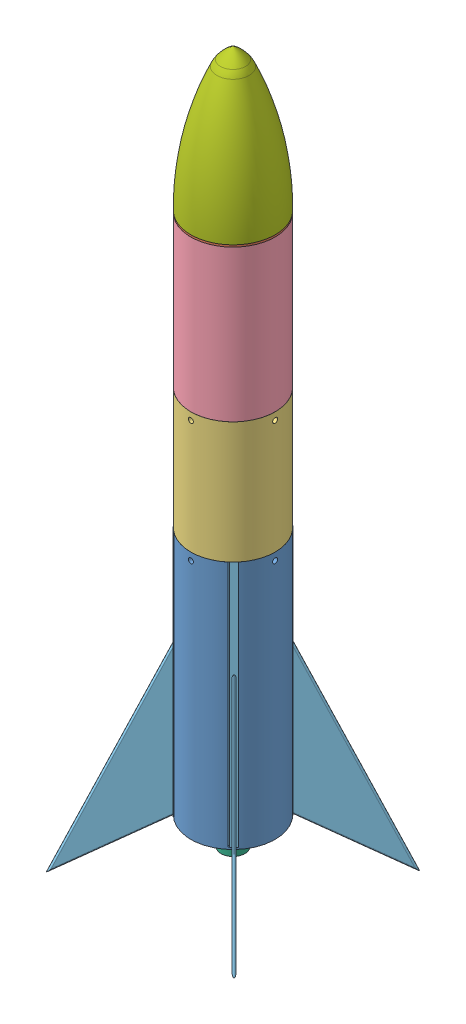
SolidWorks assembly Rocket Assembly, configuration Default. Lengths in mm.
Overall size (188.14 717 189.2).
13 component instances, 7 part files, 44 mates.
Components (placement in the parent):
- Rocket Base-1: Rocket Base [Default] at (124.7012 34.4675 290.6801) size (84.7 250 84.7)
- Rocket Nose-1: Rocket Nose [Default] at (124.7012 553.4675 290.6801) x (-0.216347 0 0.976316) z (-0.976316 0 -0.216347) size (84.7 135 84.7)
- Rocket Electronic Bay-1: Rocket Electronic Bay [Default] at (124.7012 271.9675 290.6801) size (84.7 134.5 84.7)
- Rocket Parachute Bay-2: Rocket Parachute Bay [Default] at (124.7012 393.9675 290.6801) size (84.7 164.5 84.7)
- Rocket Fin-1: Rocket Fin [Default] at (125.0548 36.4675 290.6801) x (0 0 -1) z (1 0 0) size (69.78 298 69.78)
- Rocket Fin-2: Rocket Fin [Default] at (124.7012 36.4675 291.0336) size (69.78 298 69.78)
- Rocket Fin-3: Rocket Fin [Default] at (126.1154 36.4675 291.7408) x (-1 0 0) z (0 0 -1) size (69.78 298 69.78)
- Rocket Fin-4: Rocket Fin [Default] at (125.0548 36.4675 289.973) x (0 0 1) z (-1 0 0) size (69.78 298 69.78)
- Rocket Motor-5: Rocket Motor [Default] at (111.4194 20.2175 277.3983) size (24 114.25 24)
- Rocket Motor-6: Rocket Motor [Default] at (111.4194 20.2175 303.9619) size (24 114.25 24)
- Rocket Motor-7: Rocket Motor [Default] at (137.983 20.2175 277.3983) size (24 114.25 24)
- Rocket Motor-8: Rocket Motor [Default] at (137.983 20.2175 303.9619) size (24 114.25 24)
- Rocket Cockpit-1: Rocket Cockpit [Default] at (124.7012 553.4675 290.6801) size (84.78 143 84.78)
Mates (geometry in assembly coordinates):
- Concentric2: concentric anti-aligned: circle of Rocket Parachute Bay-1; circle of Rocket Nose-1
- Coincident3: coincident anti-aligned: plane of Rocket Parachute Bay-1 through (125.5581 470.9015 302.3142) normal (0 1 0); plane of Rocket Nose-1 through (161.0312 558.4675 268.9164) normal (0 -1 0)
- Tangent1: tangent anti-aligned: cylinder of Rocket Motor-2 through (141.5736 148.7175 279.5263) axis (0 -1 0) radius 14.125; cylinder of Rocket Motor-4 through (136.2661 148.7175 307.2733) axis (0 -1 0) radius 14.125
- Tangent2: tangent anti-aligned: cylinder of Rocket Motor-3 through (108.565 148.7175 301.7317) axis (0 -1 0) radius 14.125; cylinder of Rocket Motor-4 through (136.2661 148.7175 307.2733) axis (0 -1 0) radius 14.125
- Tangent3: tangent anti-aligned: cylinder of Rocket Motor-1 through (113.8724 148.7175 273.9847) axis (0 -1 0) radius 14.125; cylinder of Rocket Motor-3 through (108.565 148.7175 301.7317) axis (0 -1 0) radius 14.125
- Tangent4: tangent anti-aligned: cylinder of Rocket Motor-1 through (113.8724 148.7175 273.9847) axis (0 -1 0) radius 14.125; cylinder of Rocket Motor-2 through (141.5736 148.7175 279.5263) axis (0 -1 0) radius 14.125
- Coincident4: coincident aligned: plane of Rocket Motor-1 through (113.8724 34.4675 273.9847) normal (0 -1 0); plane of Rocket Motor-3 through (108.565 34.4675 301.7317) normal (0 -1 0)
- Coincident5: coincident aligned: plane of Rocket Motor-3 through (108.565 34.4675 301.7317) normal (0 -1 0); plane of Rocket Motor-4 through (136.2661 34.4675 307.2733) normal (0 -1 0)
- Coincident6: coincident aligned: plane of Rocket Motor-1 through (113.8724 34.4675 273.9847) normal (0 -1 0); plane of Rocket Motor-2 through (141.5736 34.4675 279.5263) normal (0 -1 0)
- Lock1: lock: unknown of Rocket Motor-1; unknown of Rocket Motor-2
- Lock2: lock: unknown of Rocket Motor-2; unknown of Rocket Motor-4
- Lock3: lock: unknown of Rocket Motor-3; unknown of Rocket Motor-4
- Lock4: lock: unknown of Rocket Motor-1; unknown of Rocket Motor-3
- Tangent5: tangent aligned: cylinder of Rocket Base-1 through (124.7012 284.4675 290.6801) axis (0 -1 0) radius 34.3508; cylinder of Rocket Motor-4 through (136.2661 148.7175 307.2733) axis (0 -1 0) radius 14.125
- Coincident11: coincident aligned: plane of Rocket Base-1 through (124.7012 34.4675 290.6801) normal (0 -1 0); plane of Rocket Motor-1 through (113.8724 34.4675 273.9847) normal (0 -1 0)
- Tangent6: tangent aligned: cylinder of Rocket Base-1 through (124.7012 284.4675 290.6801) axis (0 -1 0) radius 34.3508; cylinder of Rocket Motor-2 through (141.5736 148.7175 279.5263) axis (0 -1 0) radius 14.125
- Concentric3: concentric aligned: cylinder of Rocket Base-1 through (82.3505 276.9675 290.6801) axis (1 0 0) radius 2.5; cylinder of Rocket Electronic Bay-1 through (90.8512 276.9675 290.6801) axis (1 0 0) radius 2.5
- Concentric4: concentric aligned: cylinder of Rocket Base-1 through (124.7012 276.9675 248.3293) axis (0 0 1) radius 2.5; cylinder of Rocket Electronic Bay-1 through (124.7012 276.9675 256.8301) axis (0 0 1) radius 2.5
- Concentric5: concentric aligned: cylinder of Rocket Electronic Bay-1 through (82.3512 398.9675 290.6801) axis (1 0 0) radius 2.5; cylinder of Rocket Parachute Bay-2 through (90.8512 398.9675 290.6801) axis (1 0 0) radius 2.5
- Concentric6: concentric aligned: cylinder of Rocket Electronic Bay-1 through (124.7012 398.9675 248.3301) axis (0 0 1) radius 2.5; cylinder of Rocket Parachute Bay-2 through (124.7012 398.9675 256.8301) axis (0 0 1) radius 2.5
- Coincident13: coincident anti-aligned: plane of Rocket Nose-1 through (124.7012 553.4675 290.6801) normal (0 -1 0); plane of Rocket Parachute Bay-2 through (124.7012 553.4675 290.6801) normal (0 1 0)
- Coincident14: coincident anti-aligned: plane of Rocket Base-1 through (100.7651 284.4675 259.6729) normal (-0.707107 0 -0.707107); plane of Rocket Fin-1 through (100.7651 284.4675 259.6729) normal (0.707107 0 0.707107)
- Coincident15: coincident anti-aligned: plane of Rocket Base-1 through (124.7012 36.4675 290.6801) normal (0 1 0); plane of Rocket Fin-1 through (125.0548 36.4675 290.6801) normal (0 -1 0)
- Distance1: distance = 0.5 mm anti-aligned: plane of Rocket Fin-1 through (94.0476 284.4675 266.3904) normal (-0.707107 0 0.707107); plane of Rocket Base-1 through (93.6941 284.4675 266.744) normal (0.707107 0 -0.707107)
- Distance2: distance = 0.5 mm anti-aligned: plane of Rocket Fin-2 through (151.1122 284.4675 260.0265) normal (-0.707107 0 -0.707107); plane of Rocket Base-1 through (151.1122 284.4675 259.3194) normal (0.707107 0 0.707107)
- Coincident18: coincident anti-aligned: plane of Rocket Base-1 through (155.7084 284.4675 266.744) normal (0.707107 0 -0.707107); plane of Rocket Fin-2 through (155.7084 284.4675 266.744) normal (-0.707107 0 0.707107)
- Coincident19: coincident anti-aligned: plane of Rocket Base-1 through (124.7012 36.4675 290.6801) normal (0 1 0); plane of Rocket Fin-2 through (124.7012 36.4675 291.0336) normal (0 -1 0)
- Distance3: distance = 0.5 mm anti-aligned: plane of Rocket Base-1 through (93.3405 284.4675 317.0911) normal (0.707107 0 0.707107); plane of Rocket Fin-3 through (94.0476 284.4675 317.0911) normal (-0.707107 0 -0.707107)
- Coincident21: coincident anti-aligned: plane of Rocket Base-1 through (93.6941 284.4675 314.6162) normal (-0.707107 0 0.707107); plane of Rocket Fin-3 through (95.1083 284.4675 316.0304) normal (0.707107 0 -0.707107)
- Coincident22: coincident anti-aligned: plane of Rocket Base-1 through (124.7012 36.4675 290.6801) normal (0 1 0); plane of Rocket Fin-3 through (126.1154 36.4675 291.7408) normal (0 -1 0)
- Distance4: distance = 0.5 mm anti-aligned: plane of Rocket Fin-4 through (150.4051 284.4675 322.0408) normal (-0.707107 0 0.707107); plane of Rocket Base-1 through (151.1122 284.4675 322.0408) normal (0.707107 0 -0.707107)
- Coincident24: coincident anti-aligned: plane of Rocket Base-1 through (148.6373 284.4675 321.6873) normal (0.707107 0 0.707107); plane of Rocket Fin-4 through (149.3444 284.4675 320.9802) normal (-0.707107 0 -0.707107)
- Coincident25: coincident anti-aligned: plane of Rocket Base-1 through (124.7012 36.4675 290.6801) normal (0 1 0); plane of Rocket Fin-4 through (125.0548 36.4675 289.973) normal (0 -1 0)
- Concentric8: concentric anti-aligned: cylinder of Rocket Base-1 through (137.983 44.4675 303.9619) axis (0 -1 0) radius 12.25; circle of Rocket Motor-8
- Concentric9: concentric aligned: cylinder of Rocket Base-1 through (137.983 44.4675 277.3983) axis (0 -1 0) radius 12.25; cylinder of Rocket Motor-7 through (137.983 134.4675 277.3983) axis (0 -1 0) radius 12
- Concentric10: concentric aligned: cylinder of Rocket Base-1 through (111.4194 44.4675 277.3983) axis (0 -1 0) radius 12.25; cylinder of Rocket Motor-5 through (111.4194 134.4675 277.3983) axis (0 -1 0) radius 12
- Concentric11: concentric aligned: cylinder of Rocket Base-1 through (111.4194 44.4675 303.9619) axis (0 -1 0) radius 12.25; cylinder of Rocket Motor-6 through (111.4194 134.4675 303.9619) axis (0 -1 0) radius 12
- Coincident27: coincident anti-aligned: plane of Rocket Base-1 through (124.7012 134.4675 290.6801) normal (0 -1 0); plane of Rocket Motor-6 through (111.4194 134.4675 303.9619) normal (0 1 0)
- Coincident28: coincident anti-aligned: plane of Rocket Base-1 through (124.7012 134.4675 290.6801) normal (0 -1 0); plane of Rocket Motor-5 through (111.4194 134.4675 277.3983) normal (0 1 0)
- Coincident29: coincident aligned: plane of Rocket Motor-6 through (111.4194 20.2175 303.9619) normal (0 -1 0); plane of Rocket Motor-8 through (137.983 20.2175 303.9619) normal (0 -1 0)
- Coincident30: coincident aligned: plane of Rocket Motor-5 through (111.4194 20.2175 277.3983) normal (0 -1 0); plane of Rocket Motor-7 through (137.983 20.2175 277.3983) normal (0 -1 0)
- Concentric12: concentric anti-aligned: circle of Rocket Nose-1; circle of Rocket Parachute Bay-2
- Coincident32: coincident anti-aligned: plane of Rocket Nose-1 through (127.1892 688.4675 279.4525) normal (0 1 0); plane of Rocket Cockpit-1 through (124.7012 688.4675 290.6801) normal (0 -1 0)
- Concentric13: concentric aligned: circle of Rocket Nose-1; circle of Rocket Cockpit-1
